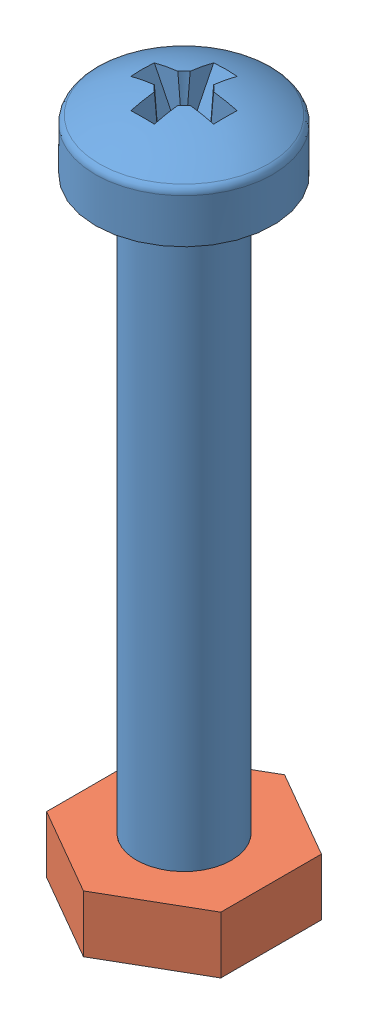
SolidWorks assembly tay_cam_asm, configuration Default. Lengths in mm.
Overall size (5.6 22.35 6.35).
2 component instances, 2 part files, 0 mates.
Components (placement in the parent):
- pan head cross recess screw_iso-12: pan head cross recess screw_iso [ISO 7045 - M3 x 20 - Z - 20N] at (16.3594 20.7872 59.0368) x (0 -1 0) z (0 0 1) size (22.35 5.6 5.6)
- hex thin nut gradeb_iso-2: hex thin nut gradeb_iso [ISO - 4036 - M3 - N] at (16.3594 -1.4128 59.0368) x (1 0 0) z (0 -1 0) size (5.5 6.35 1.8)
